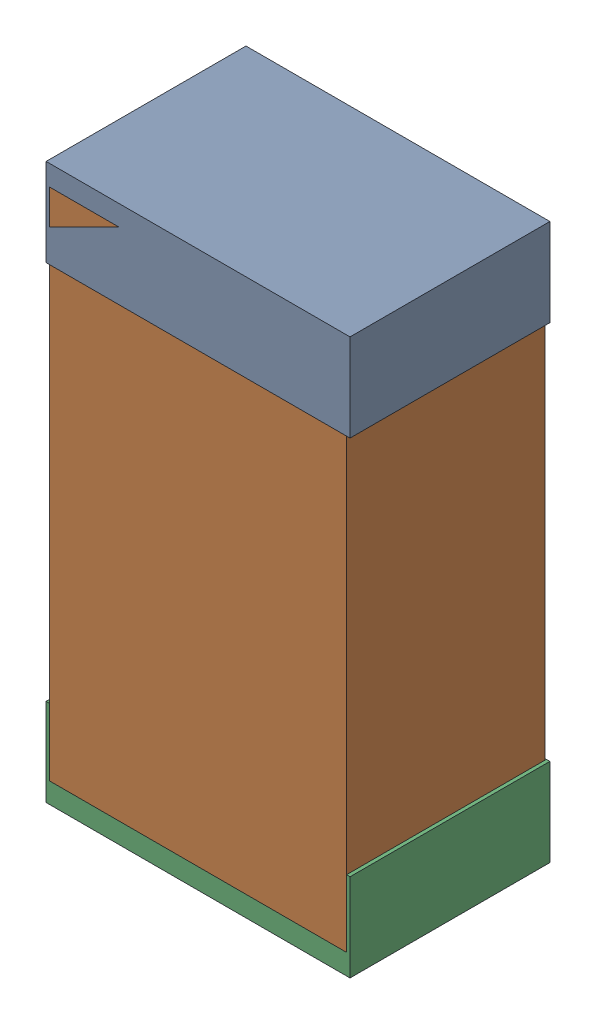
SolidWorks assembly R12Kanaloa_v2.0.0_Motor, configuration Default. Lengths in mm.
Overall size (1.3 2.38 0.85).
6 component instances, 2 part files, 0 mates.
Components (placement in the parent):
- 330415056-1: 330415056 [Default] at (41.402 72.12 -1.9574) size (1.3 0.38 0.85)
  - Extruded_2-1: Extruded_2 [Default] at origin size (1.3 0.38 0.85)
- 334787376-1: 334787376 [Default] at (41.402 71.12 -1.9524) size (1.27 2.2 0.85)
  - Extruded_16-1: Extruded_16 [Default] at origin size (1.27 2.2 0.85)
- 330415056-2: 330415056 [Default] at (41.402 70.12 -1.9574) size (1.3 0.38 0.85)
  - Extruded_2-1: Extruded_2 [Default] at origin size (1.3 0.38 0.85)
